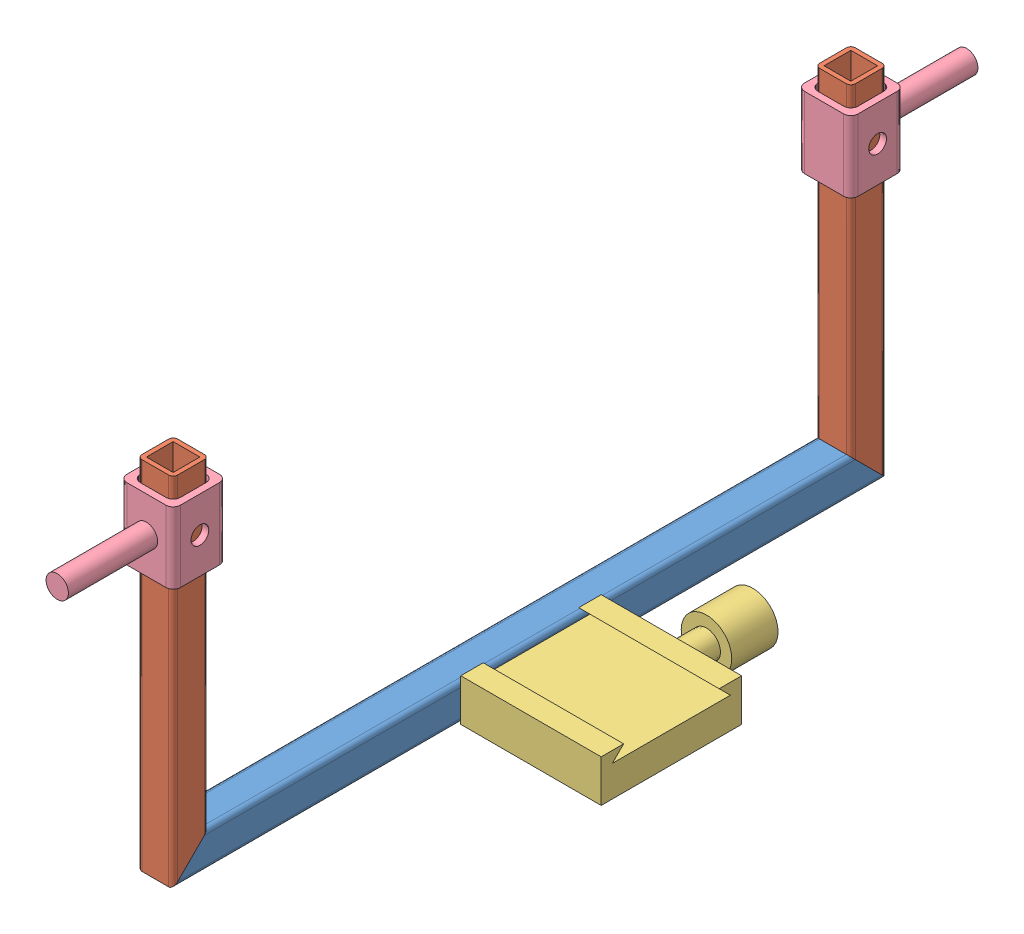
SolidWorks assembly TiltCarriage, configuration Default. Lengths in mm.
Overall size (66.28 130.18 323.85).
7 component instances, 5 part files, 17 mates.
Components (placement in the parent):
- CarriageHorizontal-1: CarriageHorizontal [Default] at (-12.9501 0 -82.0445) x (0 1 0) z (0 0 1) size (12.7 12.7 254)
- CarriageUpright-1: CarriageUpright [Default] at (-25.6501 127 171.9555) x (0 0 -1) z (0 -1 0) size (12.7 12.7 127)
- ArcaSwissMount-1: ArcaSwissMount [Default] at (-12.5501 0.1033 69.9555) x (0 0 -1) z (1 0 0) size (79 18 50)
- CarriageSlider-1: CarriageSlider [Default] at (-9.7751 120.4004 156.0805) x (0 0 1) z (1 0 0) size (50.8 25.4 19.05)
- CarriageTab-1: CarriageTab [Default] at (-25.6501 -3.175 29.0805) x (0 0 1) z (-1 0 0) size (31.75 3.17 50.8)
- CarriageUpright-2: CarriageUpright [Default] at (-12.9501 127 -82.0445) x (0 0 1) z (0 -1 0) size (12.7 12.7 127)
- CarriageSlider-2: CarriageSlider [Default] at (-9.7751 95.0004 -66.1695) x (0 0 -1) z (1 0 0) size (50.8 25.4 19.05)
Mates (geometry in assembly coordinates):
- Coincident1: coincident anti-aligned: plane of CarriageHorizontal-1 through (-12.9501 0 171.9555) normal (0 -1 0)
- Coincident2: coincident anti-aligned: plane of CarriageHorizontal-1 through (-12.9501 12.7 159.2555) normal (0 0.707107 0.707107); plane of CarriageUpright-1 through (-25.6501 12.7 159.2555) normal (0 -0.707107 -0.707107)
- Coincident3: coincident anti-aligned: line of CarriageHorizontal-1 through (-24.0626 0 171.9555) axis (1 0 0); line of CarriageUpright-1 through (-14.5376 0 171.9555) axis (-1 0 0)
- Coincident4: coincident aligned: plane of CarriageHorizontal-1 through (-12.9501 0 171.9555) normal (1 0 0); plane of CarriageUpright-1 through (-12.9501 0 171.9555) normal (1 0 0)
- Width1: width aligned: plane of CarriageSlider-1 through (-12.1564 95.0004 158.4618) normal (0 0 1); plane of CarriageUpright-1 through (-12.1564 95.0004 172.7493) normal (0 0 -1); plane of CarriageSlider-1 through (-25.6501 0 171.9555) normal (0 0 1); plane of CarriageUpright-1 through (-25.6501 0 159.2555) normal (0 0 -1)
- Width2: width aligned: plane of CarriageSlider-1 through (-12.1564 95.0004 158.4618) normal (-1 0 0); plane of CarriageUpright-1 through (-26.4439 95.0004 158.4618) normal (1 0 0); plane of CarriageSlider-1 through (-25.6501 0 171.9555) normal (-1 0 0); plane of CarriageUpright-1 through (-12.9501 0 171.9555) normal (1 0 0)
- Coincident5: coincident anti-aligned: plane of CarriageHorizontal-1 through (-12.9501 0 -82.0445) normal (0 0.707107 -0.707107); plane of CarriageUpright-2 through (-12.9501 12.7 -69.3445) normal (0 -0.707107 0.707107)
- Coincident6: coincident aligned: line of CarriageHorizontal-1 through (-24.0626 0 -82.0445) axis (1 0 0); line of CarriageUpright-2 through (-24.0626 0 -82.0445) axis (1 0 0)
- Coincident7: coincident aligned: plane of CarriageHorizontal-1 through (-12.9501 0 171.9555) normal (1 0 0); plane of CarriageUpright-2 through (-12.9501 0 -82.0445) normal (1 0 0)
- Width3: width aligned: plane of CarriageSlider-2 through (-12.1564 120.4004 -68.5507) normal (-1 0 0); plane of CarriageUpright-2 through (-26.4439 120.4004 -68.5507) normal (1 0 0); plane of CarriageSlider-2 through (-25.6501 0 -82.0445) normal (-1 0 0); plane of CarriageUpright-2 through (-12.9501 0 -82.0445) normal (1 0 0)
- Width4: width aligned: plane of CarriageSlider-2 through (-12.1564 120.4004 -68.5507) normal (0 0 -1); plane of CarriageUpright-2 through (-12.1564 120.4004 -82.8382) normal (0 0 1); plane of CarriageSlider-2 through (-12.9501 0 -82.0445) normal (0 0 -1); plane of CarriageUpright-2 through (-12.9501 0 -69.3445) normal (0 0 1)
- Coincident9: coincident aligned: plane of CarriageSlider-1 through (-9.7751 120.4004 156.0805) normal (0 1 0); plane of CarriageSlider-2 through (-9.7751 120.4004 -66.1695) normal (0 1 0)
- Concentric1: concentric: cylinder of CarriageHorizontal-1 through (-19.3001 12.701 35.4305) axis (0 -1 0) radius 2.032; cylinder of CarriageTab-1 through (-19.3001 0 35.4305) axis (0 -1 0) radius 2.286
- Coincident10: coincident: plane of CarriageHorizontal-1 through (-12.9501 0 171.9555) normal (0 -1 0); plane of CarriageTab-1 through (-25.6501 0 29.0805) normal (0 1 0)
- Concentric2: concentric aligned: cylinder of CarriageHorizontal-1 through (-19.3001 12.701 54.4805) axis (0 -1 0) radius 2.032; cylinder of CarriageTab-1 through (-19.3001 0 54.4805) axis (0 -1 0) radius 2.286
- Concentric3: concentric: cylinder of ArcaSwissMount-1 through (12.4499 6.4533 44.9555) axis (0 -1 0) radius 4.7625; cylinder of CarriageTab-1 through (12.4499 0 44.9555) axis (0 -1 0) radius 4.7625
- Parallel1: parallel anti-aligned: plane of CarriageHorizontal-1 through (-12.9501 0 171.9555) normal (1 0 0); plane of ArcaSwissMount-1 through (-12.5501 0.1033 69.9555) normal (-1 0 0)
